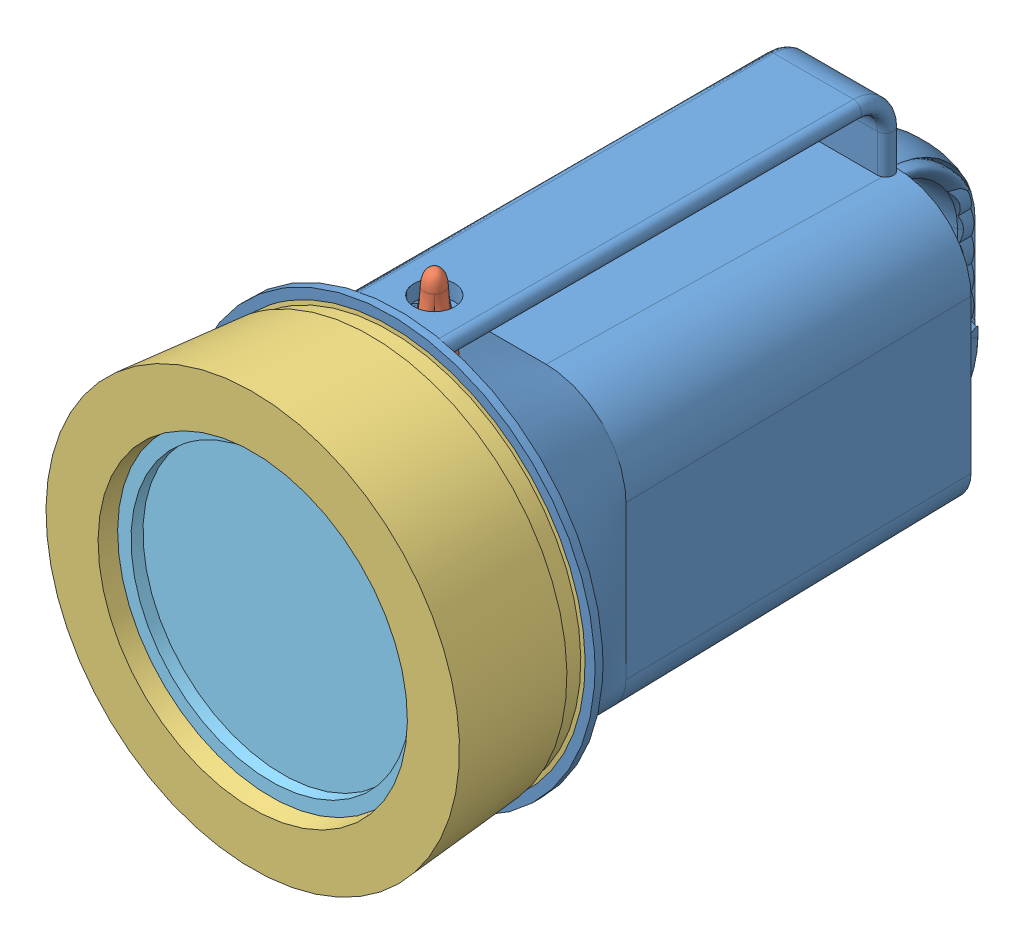
SolidWorks assembly FLASHLIGHT, configuration Default. Lengths in mm.
Overall size (183.04 183.04 277.1).
11 component instances, 8 part files, 9 mates.
Components (placement in the parent):
- HOUSING-1: HOUSING [Default] at (60.2134 96.1719 195.9054) size (145.47 130.18 266.94)
- SWITCH-1: SWITCH [Default] at (60.2134 136.8119 184.4754) size (17.84 31.52 17.84)
- CAPANDLENS-1: CAPANDLENS [Default] at (141.169 96.4264 125.6991) x (-0.568452 0.822717 0) z (0 0 1) size (131.57 131.57 76.83)
  - LENSCAP-1: LENSCAP [Default] at (45.81 66.7482 116.5613) size (131.57 131.57 43.81)
  - O-RING-1: O-RING [Default] at (45.81 66.7482 109.5763) size (113.67 113.67 3.17)
  - LENSANDBULB-1: LENSANDBULB [Default] at (6.0079 -14.3288 1.869) size (114.3 114.3 71.12)
    - LENS-1: LENS [Default] at (39.8021 81.077 102.6273) size (114.3 114.3 68.58)
    - BULB-1: BULB [Default] at (39.8021 81.077 53.0973) size (29.97 28.98 48.47)
- BATTERYANDPLATE-1: BATTERYANDPLATE [Default] at (147.5044 139.3688 55.3882) x (-0.004168 -0.999991 0) z (-0.999991 0.004168 0) size (68.58 119.38 68.58)
  - BATTERY-1: BATTERY [Default] at (43.5603 2.7223 87.1103) size (68.58 114.3 68.58)
  - BATTERYPLATE-1: BATTERYPLATE [Default] at (43.5603 106.8623 87.1103) size (68.58 15.24 68.58)
Mates (geometry in assembly coordinates):
- Coincident1: coincident aligned: plane of HOUSING-1 through (60.2134 96.1719 195.9054) normal (1 0 0); plane of SWITCH-1 through (60.2134 136.8119 184.4754) normal (1 0 0)
- Coincident4: coincident: line of HOUSING-1 through (60.2134 154.5919 184.4754) axis (0 1 0); plane of SWITCH-1 through (60.2134 136.8119 184.4754) normal (0 0 1)
- Distance1: distance = 2.54 mm: point of SWITCH-1; plane of HOUSING-1 through (72.9134 159.6719 63.8254) normal (0 1 0)
- Coincident7: coincident: plane of HOUSING-1 through (60.2134 96.1719 195.9054) normal (1 0 0); line of CAPANDLENS-1/O-RING-1 through (60.2134 96.1719 203.1199) axis (0 0 1)
- Coincident8: coincident: plane of HOUSING-1 through (60.2134 96.1719 195.9054) normal (0 1 0); line of CAPANDLENS-1/O-RING-1 through (60.2134 96.1719 203.1199) axis (0 0 1)
- Coincident11: coincident: plane of HOUSING-1 through (60.2134 96.1719 195.9054) normal (1 0 0); line of BATTERYANDPLATE-1/BATTERY-1 through (60.2134 96.1719 157.1704) axis (0 0 1)
- Coincident12: coincident: plane of HOUSING-1 through (60.2134 96.1719 195.9054) normal (0 1 0); line of BATTERYANDPLATE-1/BATTERY-1 through (60.2134 96.1719 157.1704) axis (0 0 1)
- Coincident14: coincident anti-aligned: plane of HOUSING-1 through (42.6264 96.1719 58.1104) normal (0 0 1); plane of BATTERYANDPLATE-1/BATTERY-1 through (60.2134 96.1719 58.1104) normal (0 0 -1)
- Coincident15: coincident anti-aligned: plane of HOUSING-1 through (60.2134 96.1719 198.4454) normal (0 0 1); plane of CAPANDLENS-1/LENSCAP-1 through (60.2134 96.1719 198.4454) normal (0 0 -1)
